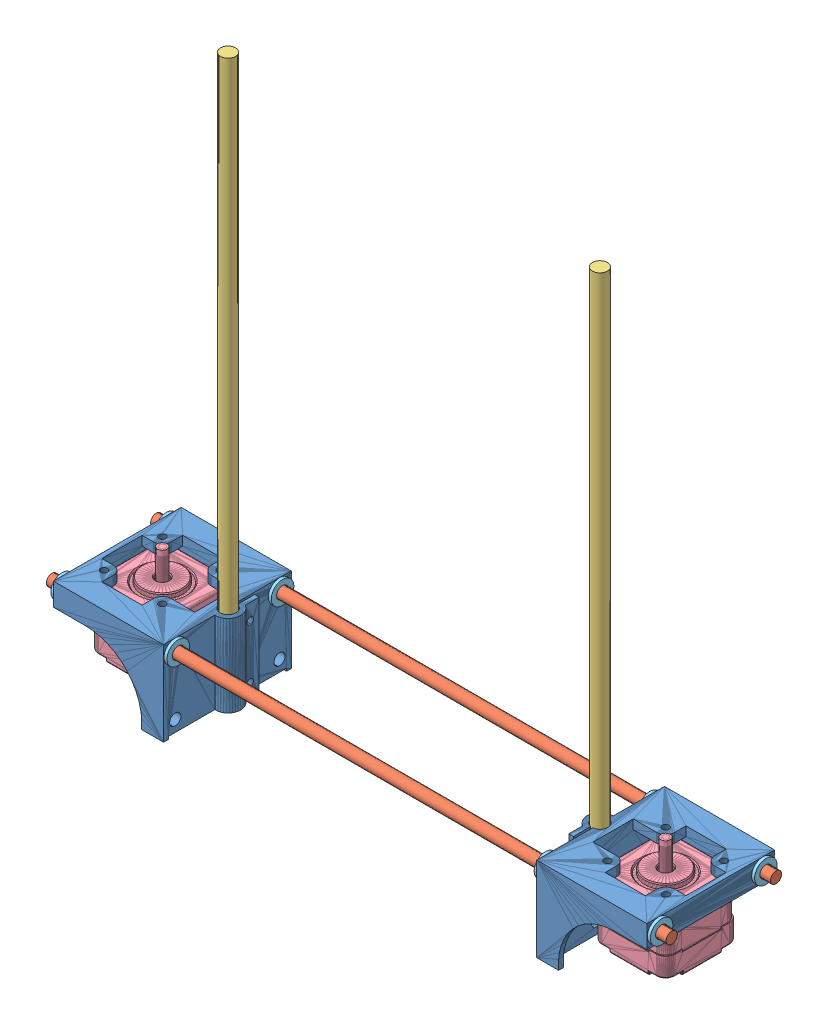
SolidWorks assembly Base central com lisa, configuration Valor predeterminado. Lengths in mm.
Overall size (330 301.4 68.02).
16 component instances, 5 part files, 35 mates.
Components (placement in the parent):
- base-1: base [Valor predeterminado] at (-58.66 43.6 -68) x (1 0 0) z (0 -1 0) size (65.75 68 45)
- base-2: base [Valor predeterminado] at (257.34 43.6 -0.0186) x (-1 0 0) z (0 -1 0) size (65.75 68 45)
- Barra roscada 6mm-1: Barra roscada 6mm [330 x 6mm] at (-65.66 37.575 -6.25) x (0 0 -1) z (1 0 0) size (6 6 330)
- Barra roscada 6mm-2: Barra roscada 6mm [330 x 6mm] at (-65.66 37.575 -61.7686) x (0 0 -1) z (1 0 0) size (6 6 330)
- Barra lisa-1: Barra lisa [300 de 8mm] at (0.35 0 -34) x (-0.276634 0 -0.960975) z (0 1 0) size (8 8 300)
- Barra lisa-2: Barra lisa [300 de 8mm] at (198.33 0 -34.0186) x (-0.276634 0 -0.960975) z (0 1 0) size (8 8 300)
- NEMA17_33 MOTOR-1: NEMA17_33 MOTOR [Valor predeterminado] at (-15.1468 5.5584 -53.4978) x (0 1 0) z (0 0 1) size (49 39 39)
- NEMA17_33 MOTOR-2: NEMA17_33 MOTOR [Valor predeterminado] at (252.8278 5.5584 -53.5191) x (0 1 0) z (0 0 1) size (49 39 39)
- Plain Washer Normal Grade A_ISO-1: Plain Washer Normal Grade A_ISO [Washer ISO 7089 - 6] at (258.94 37.575 -6.25) size (1.6 12 12)
- Plain Washer Normal Grade A_ISO-2: Plain Washer Normal Grade A_ISO [Washer ISO 7089 - 6] at (258.94 37.575 -61.7686) size (1.6 12 12)
- Plain Washer Normal Grade A_ISO-3: Plain Washer Normal Grade A_ISO [Washer ISO 7089 - 6] at (198.68 37.575 -6.25) size (1.6 12 12)
- Plain Washer Normal Grade A_ISO-4: Plain Washer Normal Grade A_ISO [Washer ISO 7089 - 6] at (198.68 37.575 -61.7686) size (1.6 12 12)
- Plain Washer Normal Grade A_ISO-6: Plain Washer Normal Grade A_ISO [Washer ISO 7089 - 6] at (1.6 37.575 -61.7686) size (1.6 12 12)
- Plain Washer Normal Grade A_ISO-7: Plain Washer Normal Grade A_ISO [Washer ISO 7089 - 6] at (-58.66 37.575 -6.25) size (1.6 12 12)
- Plain Washer Normal Grade A_ISO-8: Plain Washer Normal Grade A_ISO [Washer ISO 7089 - 6] at (-58.66 37.575 -61.7686) size (1.6 12 12)
- Plain Washer Normal Grade A_ISO-9: Plain Washer Normal Grade A_ISO [Washer ISO 7089 - 6] at (1.6 37.575 -6.25) size (1.6 12 12)
Mates (geometry in assembly coordinates):
- Coincidente2: coincident anti-aligned: plane of base-1 through (-6.68 0 -2.51) normal (0 -1 0); plane of assembly through (0 0 0) normal (0 1 0)
- Paralelo5: parallel aligned: plane of base-1 through (0 43.6 -27.2906) normal (1 0 0); plane of assembly through (0 0 0) normal (1 0 0)
- Paralelo2: parallel anti-aligned: plane of base-1 through (0 0 -2.51) normal (1 0 0); plane of base-2 through (198.68 0 -65.5086) normal (-1 0 0)
- Concêntrico1: concentric anti-aligned: circle of base-1; cylinder of Barra roscada 6mm-1 through (264.34 37.575 -6.25) axis (-1 0 0) radius 3
- Concêntrico2: concentric aligned: circle of base-2; cylinder of Barra roscada 6mm-1 through (264.34 37.575 -6.25) axis (-1 0 0) radius 3
- Distância1: distance = 7 mm aligned: plane of Barra roscada 6mm-1 through (-65.66 37.575 -6.25) normal (-1 0 0); plane of base-1 through (-58.66 43.6 0) normal (-1 0 0)
- Distância2: distance = 7 mm aligned: plane of base-2 through (257.34 34.1496 -5.2562) normal (1 0 0); plane of Barra roscada 6mm-1 through (264.34 37.575 -6.25) normal (1 0 0)
- Concêntrico3: concentric anti-aligned: circle of base-1; cylinder of Barra roscada 6mm-2 through (264.34 37.575 -61.7686) axis (-1 0 0) radius 3
- Distância3: distance = 7 mm aligned: plane of Barra roscada 6mm-2 through (264.34 37.575 -61.7686) normal (1 0 0); plane of base-2 through (257.34 40.535 -60.6912) normal (1 0 0)
- Concêntrico4: concentric anti-aligned: circle of base-1; cylinder of Barra lisa-1 through (0.35 300 -34) axis (0 -1 0) radius 4
- Coincidente11: coincident aligned: plane of base-1 through (-6.68 0 -2.51) normal (0 -1 0); plane of Barra lisa-1 through (0.35 0 -34) normal (0 -1 0)
- Concêntrico5: concentric anti-aligned: circle of base-2; cylinder of Barra lisa-2 through (198.33 300 -34.0186) axis (0 -1 0) radius 4
- Coincidente12: coincident aligned: plane of base-2 through (205.36 0 -65.5086) normal (0 -1 0); plane of Barra lisa-2 through (198.33 0 -34.0186) normal (0 -1 0)
- Concêntrico6: concentric aligned: circle of base-1; cylinder of NEMA17_33 MOTOR-1 through (-50.15 5.6 -18.5) axis (0 1 0) radius 1.6
- Paralelo3: parallel aligned: plane of base-1 through (-58.66 43.6 0) normal (0 0 1); plane of NEMA17_33 MOTOR-1 through (-24.1473 27.6 -14.4973) normal (0 0 1)
- Coincidente14: coincident anti-aligned: plane of base-1 through (-56.15 38.6 -23.3) normal (0 -1 0); plane of NEMA17_33 MOTOR-1 through (-50.3378 38.6 -19.9851) normal (0 1 0)
- Concêntrico7: concentric aligned: circle of base-2; cylinder of NEMA17_33 MOTOR-2 through (248.83 5.6 -49.5186) axis (0 1 0) radius 1.6
- Paralelo4: parallel aligned: plane of base-2 through (257.34 43.6 -0.0186) normal (0 0 1); plane of NEMA17_33 MOTOR-2 through (222.8273 27.6 -14.5186) normal (0 0 1)
- Coincidente16: coincident anti-aligned: plane of base-2 through (254.83 38.6 -55.5186) normal (0 -1 0); plane of NEMA17_33 MOTOR-2 through (246.8773 38.6 -47.5686) normal (0 1 0)
- Concêntrico8: concentric aligned: cylinder of Barra roscada 6mm-1 through (264.34 37.575 -6.25) axis (-1 0 0) radius 3; cylinder of Plain Washer Normal Grade A_ISO-1 through (224.015 37.575 -6.25) axis (-1 0 0) radius 3.2
- Concêntrico9: concentric aligned: cylinder of Barra roscada 6mm-2 through (264.34 37.575 -61.7686) axis (-1 0 0) radius 3; cylinder of Plain Washer Normal Grade A_ISO-2 through (224.015 37.575 -61.7686) axis (-1 0 0) radius 3.2
- Concêntrico10: concentric aligned: cylinder of Barra roscada 6mm-1 through (264.34 37.575 -6.25) axis (-1 0 0) radius 3; cylinder of Plain Washer Normal Grade A_ISO-3 through (163.755 37.575 -6.25) axis (-1 0 0) radius 3.2
- Concêntrico11: concentric aligned: cylinder of Barra roscada 6mm-2 through (264.34 37.575 -61.7686) axis (-1 0 0) radius 3; cylinder of Plain Washer Normal Grade A_ISO-4 through (163.755 37.575 -61.7686) axis (-1 0 0) radius 3.2
- Concêntrico12: concentric aligned: cylinder of Barra roscada 6mm-2 through (264.34 37.575 -61.7686) axis (-1 0 0) radius 3; cylinder of Plain Washer Normal Grade A_ISO-6 through (-33.325 37.575 -61.7686) axis (-1 0 0) radius 3.2
- Concêntrico13: concentric aligned: cylinder of Barra roscada 6mm-1 through (264.34 37.575 -6.25) axis (-1 0 0) radius 3; cylinder of Plain Washer Normal Grade A_ISO-7 through (-93.585 37.575 -6.25) axis (-1 0 0) radius 3.2
- Concêntrico141: concentric aligned: cylinder of Barra roscada 6mm-2 through (264.34 37.575 -61.7686) axis (-1 0 0) radius 3; cylinder of Plain Washer Normal Grade A_ISO-8 through (-93.585 37.575 -61.7686) axis (-1 0 0) radius 3.2
- Concêntrico15: concentric aligned: cylinder of Barra roscada 6mm-1 through (264.34 37.575 -6.25) axis (-1 0 0) radius 3; cylinder of Plain Washer Normal Grade A_ISO-9 through (-33.325 37.575 -6.25) axis (-1 0 0) radius 3.2
- Coincidente17: coincident anti-aligned: plane of base-1 through (-58.66 43.6 -68) normal (-1 0 0); plane of Plain Washer Normal Grade A_ISO-8 through (-58.66 40.775 -61.7686) normal (1 0 0)
- Coincidente18: coincident anti-aligned: plane of base-1 through (-58.66 40.535 -7.3274) normal (-1 0 0); plane of Plain Washer Normal Grade A_ISO-7 through (-58.66 40.775 -6.25) normal (1 0 0)
- Coincidente19: coincident anti-aligned: plane of base-1 through (0 37.575 -3.1) normal (1 0 0); plane of Plain Washer Normal Grade A_ISO-9 through (0 43.575 -6.25) normal (-1 0 0)
- Coincidente20: coincident anti-aligned: plane of base-1 through (0 40.6771 -62.297) normal (1 0 0); plane of Plain Washer Normal Grade A_ISO-6 through (0 43.575 -61.7686) normal (-1 0 0)
- Coincidente21: coincident anti-aligned: plane of base-2 through (198.68 40.535 -60.6912) normal (-1 0 0); plane of Plain Washer Normal Grade A_ISO-4 through (198.68 40.775 -61.7686) normal (1 0 0)
- Coincidente22: coincident anti-aligned: plane of base-2 through (257.34 40.535 -60.6912) normal (1 0 0); plane of Plain Washer Normal Grade A_ISO-2 through (257.34 43.575 -61.7686) normal (-1 0 0)
- Coincidente23: coincident anti-aligned: plane of base-2 through (257.34 43.6 -0.0186) normal (1 0 0); plane of Plain Washer Normal Grade A_ISO-1 through (257.34 43.575 -6.25) normal (-1 0 0)
- Coincidente24: coincident anti-aligned: plane of base-2 through (198.68 40.6771 -5.7216) normal (-1 0 0); plane of Plain Washer Normal Grade A_ISO-3 through (198.68 40.775 -6.25) normal (1 0 0)
